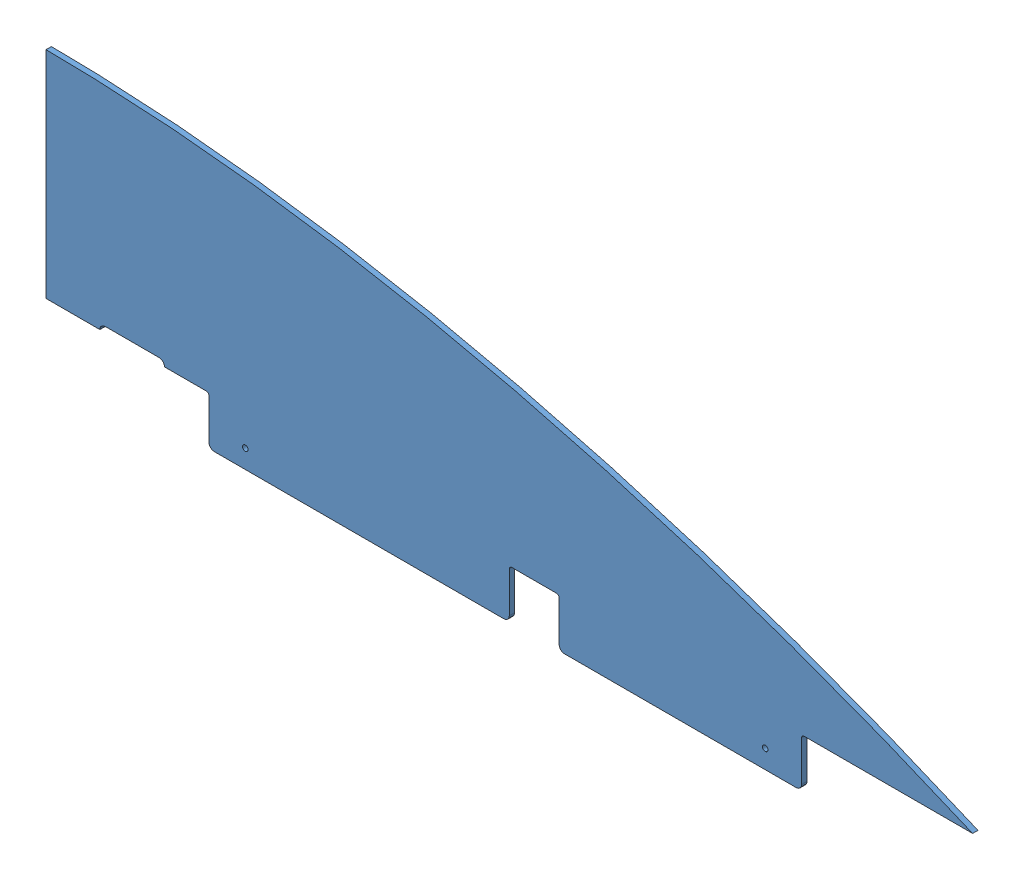
SolidWorks assembly GE-19082-Blue, configuration Default. Lengths in mm.
Overall size (1092.2 311.15 82.8).
3 component instances, 3 part files, 6 mates.
Components (placement in the parent):
- GE-19082-1: GE-19082 [Default] at origin size (1092.2 311.15 6.35)
- GE-19082-Left-Blue-Vinyl-1: GE-19082-Left-Blue-Vinyl [Default] at (0 0 -0.127) size (1092.2 254 0.13)
- GE-19082-Right-Blue-Vinyl-1: GE-19082-Right-Blue-Vinyl [Default] at (0 0 6.35) size (1092.2 254 0.13)
Mates (geometry in assembly coordinates):
- Coincident2: coincident: plane of assembly; plane of assembly; plane of GE-19082-1 through (0 254 6.35) normal (-1 0 0); plane of GE-19082-Left-Blue-Vinyl-1 through (0 254 0) normal (-1 0 0)
- Coincident4: coincident: plane of assembly; plane of assembly; plane of GE-19082-1 through (566.5746 179.041 0) normal (0 0 -1); plane of GE-19082-Left-Blue-Vinyl-1 through (566.5746 179.041 0) normal (0 0 1)
- Coincident5: coincident: plane of assembly; plane of assembly; plane of GE-19082-1 through (566.5746 179.041 6.35) normal (0 0 1); plane of GE-19082-Right-Blue-Vinyl-1 through (566.5746 179.041 6.35) normal (0 0 -1)
- Coincident6: coincident: plane of assembly; plane of assembly; plane of GE-19082-1 through (0 254 6.35) normal (-1 0 0); plane of GE-19082-Right-Blue-Vinyl-1 through (0 254 6.477) normal (-1 0 0)
- Coincident7: coincident: plane of assembly; plane of assembly; plane of GE-19082-1 through (0 0 6.35) normal (0 -1 0); plane of GE-19082-Right-Blue-Vinyl-1 through (0 0 6.477) normal (0 -1 0)
- Coincident8: coincident: plane of assembly; plane of assembly; plane of GE-19082-1 through (0 0 6.35) normal (0 -1 0); plane of GE-19082-Left-Blue-Vinyl-1 through (0 0 0) normal (0 -1 0)
